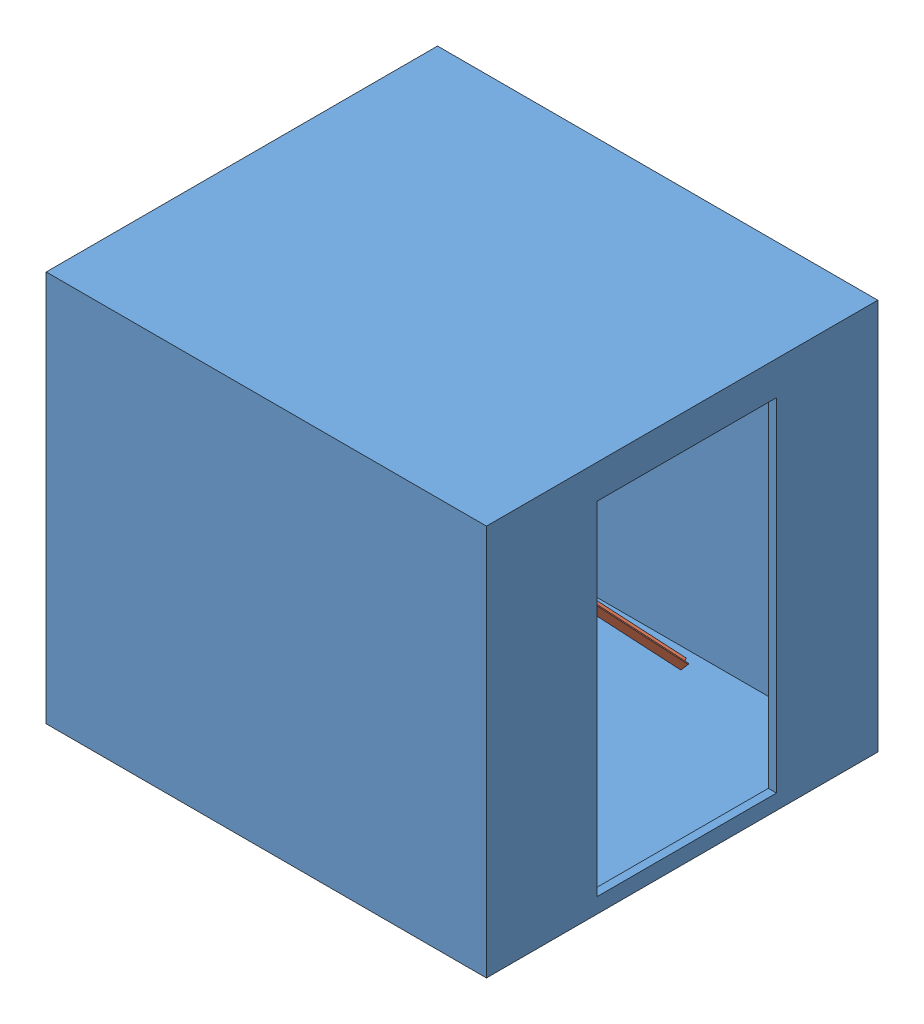
SolidWorks assembly УглЛифт, configuration По умолчанию. Lengths in mm.
Overall size (2700 2400 2400).
2 component instances, 2 part files, 2 mates.
Components (placement in the parent):
- Лифт-1: Лифт [По умолчанию] at (1112.8553 1109.6984 1104.1056) size (2700 2400 2400)
- Уголок65-1: Уголок65 [По умолчанию] at (1301.9936 3328.5757 946.1697) x (0.636225 -0.577076 -0.512055) z (0.416525 -0.301742 0.857589) size (3000 65 65)
Mates (geometry in assembly coordinates):
- Расстояние1: distance = 300 mm: point of Уголок65-1; point of Лифт-1
- Расстояние4: distance = 920.5719 mm: point of Лифт-1; point of Уголок65-1
